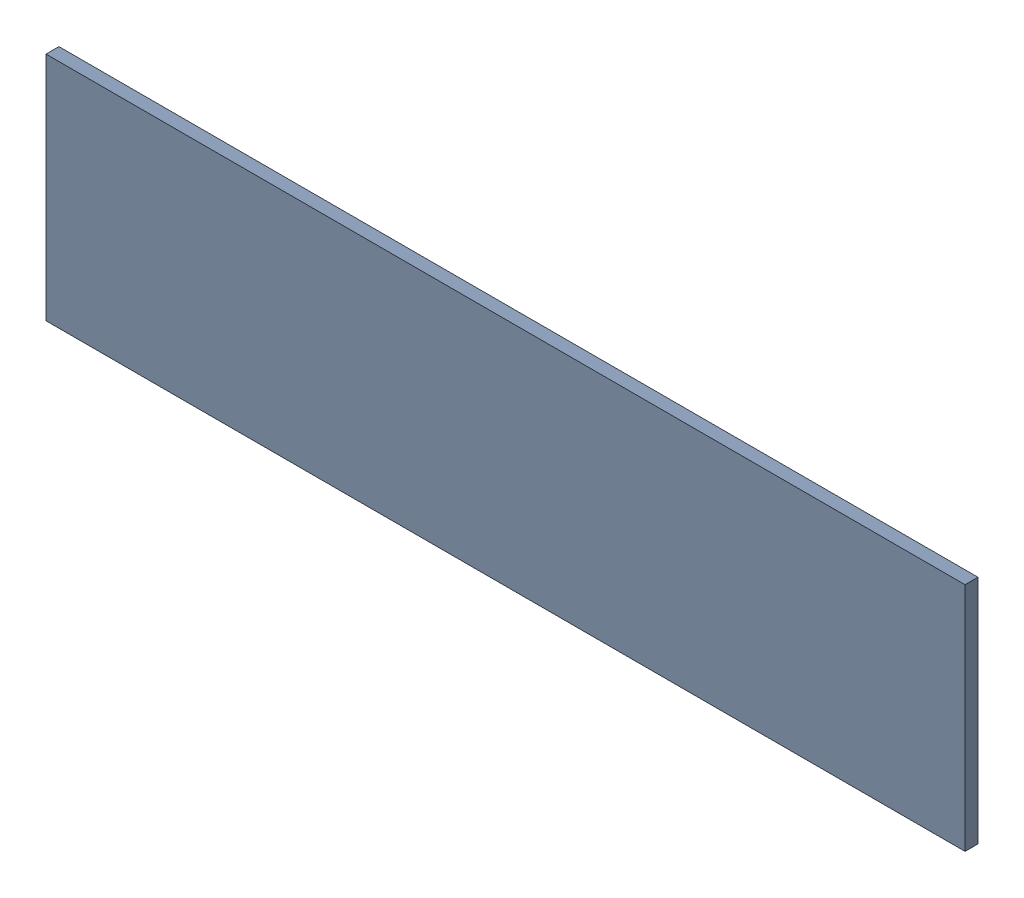
SolidWorks assembly PS-, configuration Default. Lengths in mm.
Overall size (1.8 0.45 0.03).
4 component instances, 1 part files, 0 mates.
Components (placement in the parent):
- 6701982208-1:  [Default] at (27.7 14.8 0) (suppressed, hidden)
- 6327396352-1: 6327396352 [Default] at (-3.4196 1.2245 0) size (1.8 0.45 0.03)
  - 6701982208-1:  [Default] at (27.7 14.8 0) (suppressed, hidden)
  - Extruded-24-1: Extruded-24 [Default] at origin size (1.8 0.45 0.03)
